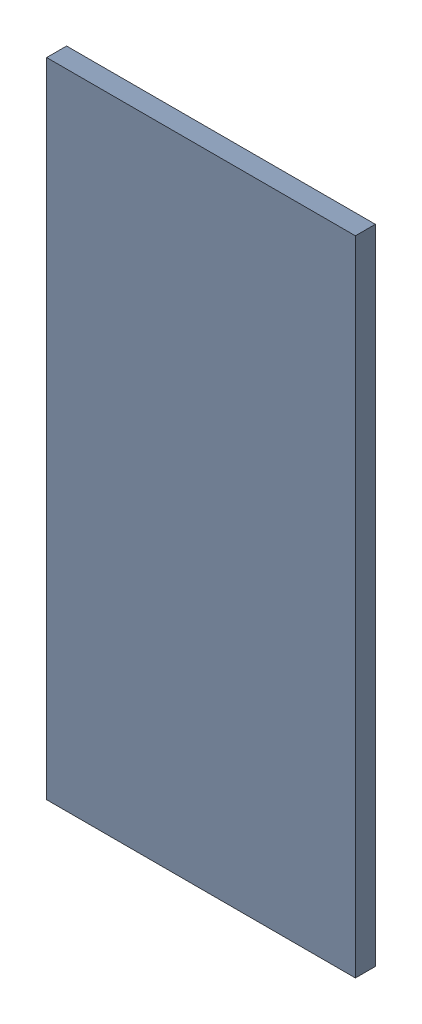
SolidWorks assembly Pad ADXL345-2(22.2mm,58.097mm) on Top Layer, configuration Predeterminado. Lengths in mm.
Overall size (0.55 1.15 0.04).
2 component instances, 1 part files, 0 mates.
Components (placement in the parent):
- Pad ADXL345-2(22.2mm,58.097mm) on Top Layer-1-1: Pad ADXL345-2(22.2mm,58.097mm) on Top Layer-1 [Predeterminado] at (-68.317 -44.187 -0.0457) size (0.55 1.15 0.04)
  - Pad ADXL345-2(22.2mm,58.097mm) on Top Layer-Part-1-1: Pad ADXL345-2(22.2mm,58.097mm) on Top Layer-Part-1 [Predeterminado] at origin size (0.55 1.15 0.04)
